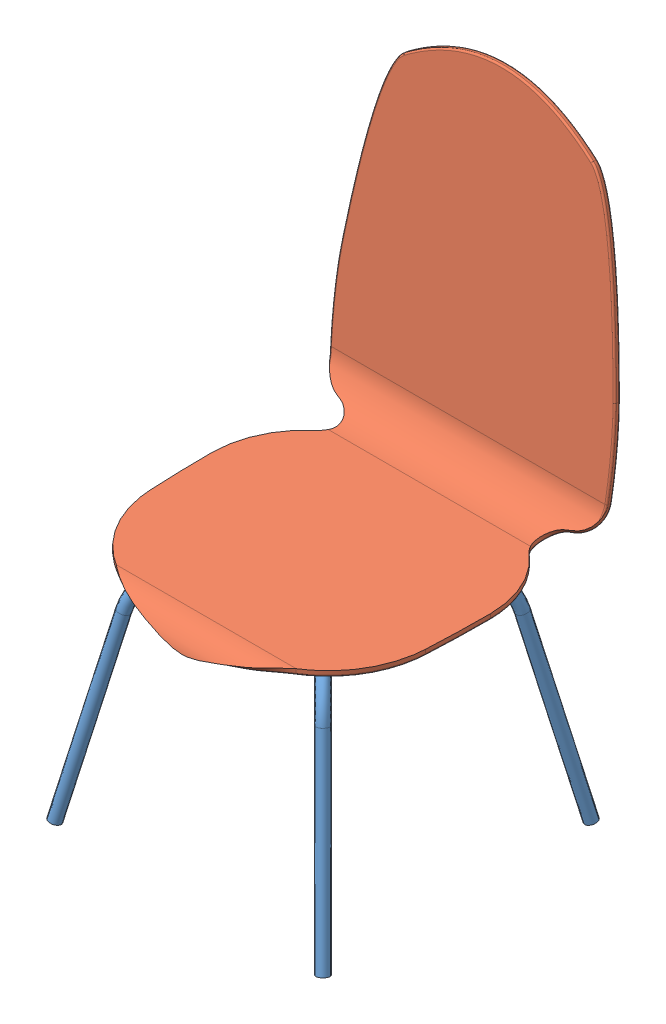
SolidWorks assembly Chair, configuration Default. Lengths in mm.
Overall size (538.62 1033.42 605.57).
2 component instances, 2 part files, 3 mates.
Components (placement in the parent):
- Chair Leg-1: Chair Leg [Default<As Machined>] at origin size (501.77 413.41 501.77)
- Chair Seat-1: Chair Seat [Default] at (0 410.65 -90.7097) size (538.62 654.12 605.57)
Mates (geometry in assembly coordinates):
- Tangent2: tangent anti-aligned: cylinder of Chair Leg-1 through (110.3706 400 -110.3706) axis (-0.707107 0 0.707107) radius 10.65; plane of Chair Seat-1 through (-250 410.65 -190.7097) normal (0 -1 0)
- Tangent3: tangent anti-aligned: cylinder of Chair Leg-1 through (110.3706 400 110.3706) axis (-0.707107 0 -0.707107) radius 10.65; plane of Chair Seat-1 through (-250 410.65 -190.7097) normal (0 -1 0)
- Coincident1: coincident aligned: plane of Chair Seat-1 through (0 410.65 -90.7097) normal (1 0 0)
